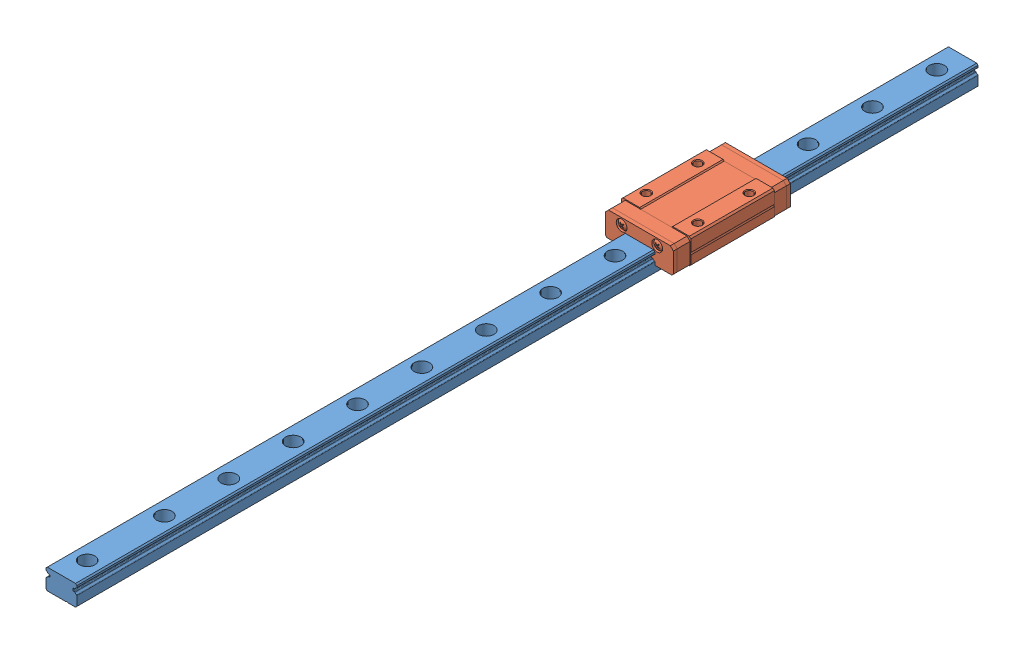
SolidWorks assembly MGN12 Assembly, configuration 2 X 12C. Lengths in mm.
Overall size (27 13.07 350).
2 component instances, 2 part files, 13 mates.
Components (placement in the parent):
- MGN12 LINEAR GUIDE RAIL, CONFIGURABLE-1: MGN12 LINEAR GUIDE RAIL, CONFIGURABLE [350 mm] at (0 5.5 0)
- MGN12H, LINEAR GUIDE BLOCK-1: MGN12H, LINEAR GUIDE BLOCK [Default] at (0 5.5 -72.1787)
Mates (geometry in assembly coordinates):
- Coincident3: coincident aligned: plane of ? through (0 0 -21.2589) normal (1 0 0)
- Coincident6: coincident aligned: plane of ? through (0 0 25.6374) normal (0 1 0)
- Coincident7: coincident aligned: plane of ? through (0 0 25.6374) normal (1 0 0)
- Coincident8: coincident aligned: plane of ? through (0 8.1964 46.1339) normal (1 0 0)
- Coincident9: coincident aligned: plane of ? through (0 0 46.1339) normal (0 1 0)
- LimitDistance1: limit distance = 224.4787 mm aligned: plane of MGN12H, LINEAR GUIDE BLOCK-1 through (-5.75 4.1421 -49.4787) normal (0 0 1); plane of MGN12 LINEAR GUIDE RAIL, CONFIGURABLE-1 through (-5.7336 4.1459 175) normal (0 0 1)
- LimitDistance2: limit distance = 80.1213 mm aligned: plane of MGN12H, LINEAR GUIDE BLOCK-1 through (5.75 4.1421 -94.8787) normal (0 0 -1); plane of MGN12 LINEAR GUIDE RAIL, CONFIGURABLE-1 through (-5.7336 4.1459 -175) normal (0 0 -1)
- Coincident18: coincident aligned: plane of MGN12 LINEAR GUIDE RAIL, CONFIGURABLE-1 through (0 5.5 0) normal (0 1 0); plane of MGN12H, LINEAR GUIDE BLOCK-1 through (0 5.5 -72.1787) normal (0 1 0)
- Coincident22: coincident aligned: plane of MGN12 LINEAR GUIDE RAIL, CONFIGURABLE-1 through (0 5.5 0) normal (0 1 0); plane of MGN12H, LINEAR GUIDE BLOCK-1 through (0 5.5 -72.1787) normal (0 1 0)
- Coincident28: coincident aligned: plane of MGN12 LINEAR GUIDE RAIL, CONFIGURABLE-1 through (0 5.5 0) normal (1 0 0); plane of MGN12H, LINEAR GUIDE BLOCK-1 through (0 5.5 -72.1787) normal (1 0 0)
- Coincident30: coincident aligned: plane of MGN12 LINEAR GUIDE RAIL, CONFIGURABLE-1 through (0 5.5 0) normal (0 0 1)
- Coincident31: coincident anti-aligned: plane of MGN12 LINEAR GUIDE RAIL, CONFIGURABLE-1 through (-5.4838 0 175) normal (0 -1 0)
- Coincident32: coincident aligned: plane of MGN12H, LINEAR GUIDE BLOCK-1 through (0 5.5 -72.1787) normal (1 0 0)
